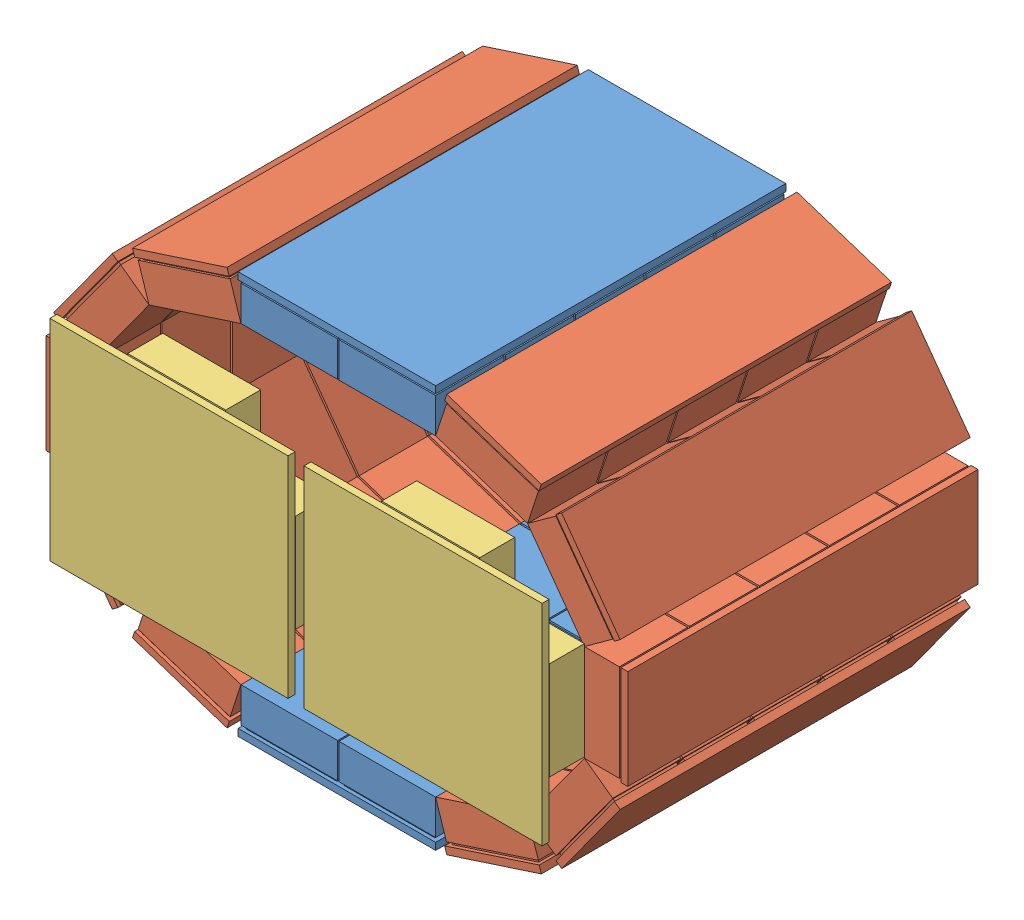
SolidWorks assembly Detector1n2, configuration Default. Lengths in mm.
Overall size (495.24 340.33 279.21).
17 component instances, 3 part files, 4 mates.
Components (placement in the parent):
- Detector1-1: Detector1 [Default] at (-155.4694 -229.9468 -178.2324) size (495.24 340.33 250)
  - top_bottomDetector-1: top_bottomDetector [Default] at (86.8452 103.3776 184.3748) size (141 32 250)
  - CshapedDetector-1: CshapedDetector [Default] at (185.8864 -33.4141 0.115) x (0.951057 0.309017 0) z (0 0 1) size (177.89 270.84 250)
    - 1Detector-1: 1Detector [Default] at (91.8512 126.8436 184.2598) size (71 32 250)
    - 1Detector-2: 1Detector [Default] at (173.0714 153.2337 184.2598) x (0.809017 0.587785 0) z (0 0 1) size (71 32 250)
    - 1Detector-4: 1Detector [Default] at (223.2683 222.3237 184.2598) x (0.309017 0.951057 0) z (0 0 1) size (71 32 250)
    - 1Detector-5: 1Detector [Default] at (223.2683 307.7237 184.2598) x (-0.309017 0.951057 0) z (0 0 1) size (71 32 250)
    - 1Detector-6: 1Detector [Default] at (173.0714 376.8138 184.2598) x (-0.809017 0.587785 0) z (0 0 1) size (71 32 250)
  - CshapedDetector-2: CshapedDetector [Default] at (57.8041 527.4581 0.115) x (-0.951057 -0.309017 0) z (0 0 1) size (177.89 270.84 250)
    - 1Detector-1: 1Detector [Default] at (91.8512 126.8436 184.2598) size (71 32 250)
    - 1Detector-2: 1Detector [Default] at (173.0714 153.2337 184.2598) x (0.809017 0.587785 0) z (0 0 1) size (71 32 250)
    - 1Detector-4: 1Detector [Default] at (223.2683 222.3237 184.2598) x (0.309017 0.951057 0) z (0 0 1) size (71 32 250)
    - 1Detector-5: 1Detector [Default] at (223.2683 307.7237 184.2598) x (-0.309017 0.951057 0) z (0 0 1) size (71 32 250)
    - 1Detector-6: 1Detector [Default] at (173.0714 376.8138 184.2598) x (-0.809017 0.587785 0) z (0 0 1) size (71 32 250)
  - top_bottomDetector-2: top_bottomDetector [Default] at (156.8452 390.6663 184.3748) x (-1 0 0) z (0 0 1) size (141 32 250)
- Detector2-1: Detector2 [Default] at (-124.3043 18.9346 160.3548) x (1 0 0) z (0 1 0) size (170 30.5 151.04)
- Detector2-2: Detector2 [Default] at (57.0559 18.3783 160.3548) x (1 0 0) z (0 1 0) size (170 30.5 151.04)
Mates (geometry in assembly coordinates):
- Coincident3: coincident anti-aligned: line of Detector1-1/CshapedDetector-2/1Detector-4 through (-209.3043 51.5752 130.1548) axis (0 -1 0); line of Detector2-1 through (-209.3043 -16.0654 130.1548) axis (0 1 0)
- Parallel1: parallel anti-aligned: line of Detector1-1/top_bottomDetector-2 through (-34.1242 128.7195 130.1548) axis (-1 0 0); line of Detector2-1 through (-159.3043 94.4567 129.8548) axis (1 0 0)
- Coincident5: coincident anti-aligned: line of Detector1-1/CshapedDetector-1/1Detector-4 through (142.0559 -17.4248 130.1548) axis (0 1 0); line of Detector2-2 through (142.0559 53.3783 130.1548) axis (0 -1 0)
- Parallel2: parallel anti-aligned: line of Detector1-1/top_bottomDetector-2 through (35.8758 128.7195 130.1548) axis (-1 0 0); line of Detector2-2 through (22.0559 93.9004 129.8548) axis (1 0 0)
